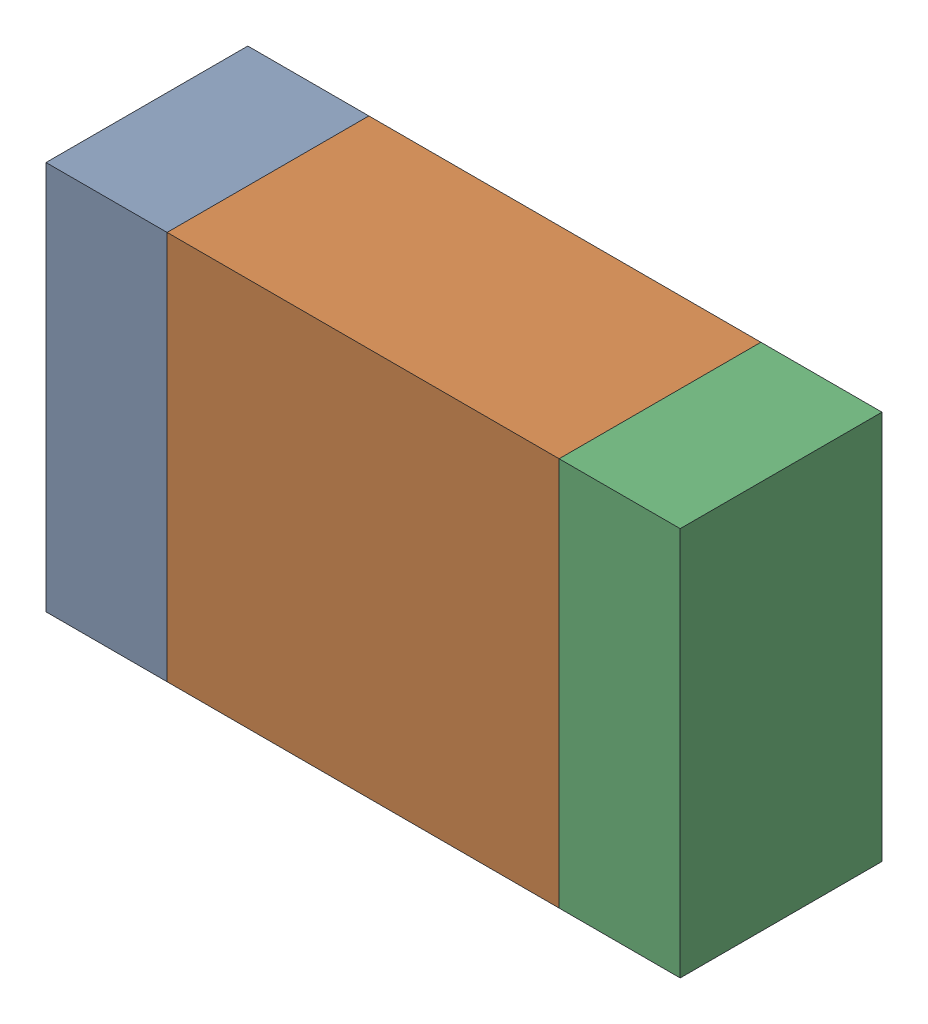
SolidWorks assembly R13-1, configuration Default. Lengths in mm.
Overall size (2.2 1.35 0.7).
6 component instances, 2 part files, 0 mates.
Components (placement in the parent):
- 959209344-1-1: 959209344-1 [Default] at (105.4089 93.8529 0) size (0.42 1.35 0.7)
  - Extruded-56-1: Extruded-56 [Default] at origin size (0.42 1.35 0.7)
- 959209480-1-1: 959209480-1 [Default] at (106.2989 93.8529 0) size (1.36 1.35 0.7)
  - Extruded-57-1: Extruded-57 [Default] at origin size (1.36 1.35 0.7)
- 959209344-1-2: 959209344-1 [Default] at (107.1889 93.8529 0) size (0.42 1.35 0.7)
  - Extruded-56-1: Extruded-56 [Default] at origin size (0.42 1.35 0.7)
